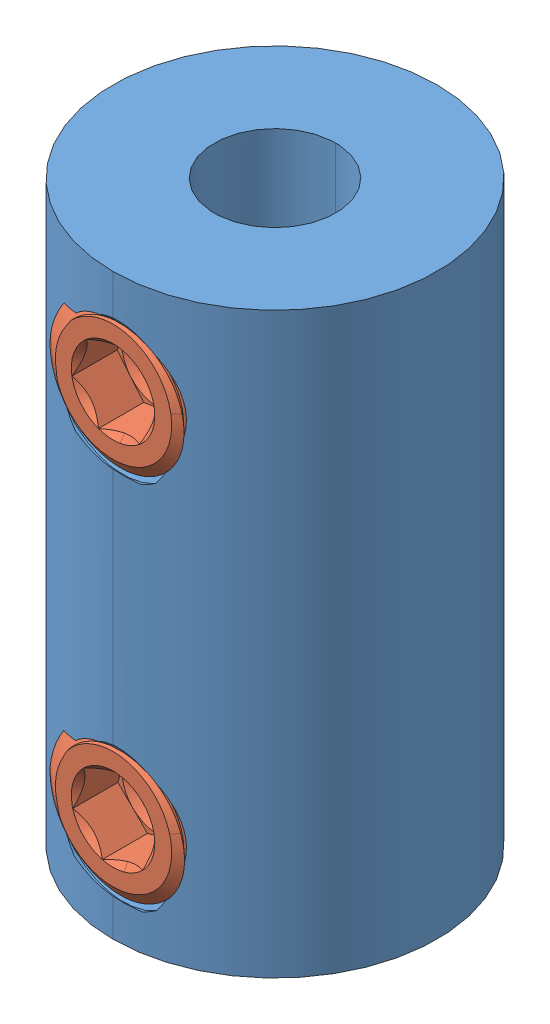
SolidWorks assembly 4mm to .25in, configuration Default. Lengths in mm.
Overall size (10.67 19.05 10.67).
4 component instances, 2 part files, 0 mates.
Components (placement in the parent):
- 625118 assembly.STEP-1: 625118 assembly.STEP [Default] at origin size (10.67 19.05 10.67)
  - 625118.STEP-1: 625118.STEP [Default] at (-89.5957 7.0024 36.013) size (10.67 19.05 10.67)
  - 632134_91375A436.STEP-1: 632134_91375A436.STEP [Default] at (-89.5957 10.4314 40.1568) x (0.259519 -0.965738 0) z (0 0 1) size (4.83 4.83 3.18)
  - 632134_91375A436.STEP-2: 632134_91375A436.STEP [Default] at (-89.5957 22.6234 40.1568) x (0.166108 -0.986108 0) z (0 0 1) size (4.83 4.83 3.18)
